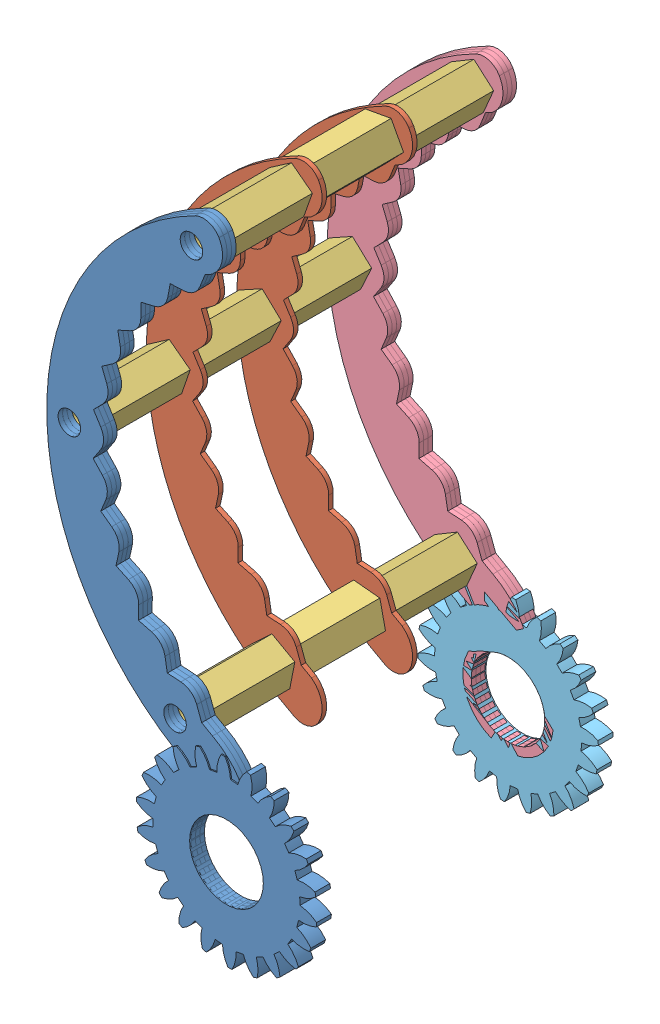
SolidWorks assembly Assem2, configuration Default. Lengths in mm.
Overall size (33.49 73.09 32.76).
17 component instances, 5 part files, 28 mates.
Components (placement in the parent):
- handle1-1: handle1 [Default] at (-7.5398 -35.6958 -27.6488) size (29.97 70.24 1.63)
- kiskac2-1: kiskac2 [Varsayılan] at (50.9968 46.7952 47.8369) size (19.45 53.92 0.5)
- araparca-1: araparca [Varsayılan] at (13.4048 24.2984 43.8369) x (0.977975 0.208721 0) z (0 0 1) size (4.68 4.59 9.5)
- araparca-2: araparca [Varsayılan] at (1.7149 46.7993 43.8369) x (0.9973 0.073437 0) z (0 0 1) size (4.68 4.59 9.5)
- araparca-3: araparca [Varsayılan] at (15.2145 70.4687 43.8369) x (0.997775 0.066667 0) z (0 0 1) size (4.68 4.59 9.5)
- araparca-4: araparca [Varsayılan] at (15.2145 70.4687 33.8369) x (-0.551736 0.834019 0) z (0 0 1) size (4.68 4.59 9.5)
- araparca-5: araparca [Varsayılan] at (1.7149 46.7993 33.8369) x (0.343925 0.938997 0) z (0 0 1) size (4.68 4.59 9.5)
- araparca-6: araparca [Varsayılan] at (13.4048 24.2984 33.8369) x (0.812716 0.582659 0) z (0 0 1) size (4.68 4.59 9.5)
- kiskac2-2: kiskac2 [Varsayılan] at (50.9968 46.7952 37.8369) size (19.45 53.92 0.5)
- araparca-13: araparca [Varsayılan] at (15.2145 70.4687 23.8369) size (4.68 4.59 9.5)
- araparca-14: araparca [Varsayılan] at (13.4048 24.2984 23.8369) size (4.68 4.59 9.5)
- araparca-15: araparca [Varsayılan] at (1.7149 46.7993 23.8369) x (0.999583 -0.028868 0) z (0 0 1) size (4.68 4.59 9.5)
- handle 2-1: handle 2 [Default] at (-16.5479 -33.7454 -75.777) size (32.9 73.09 1.63)
  - kiskac1-1: kiskac1 [Varsayılan] at (65.4233 86.2581 103.6139) size (25 65.23 0.5)
  - gear-3: gear [Default] at (35.7628 47.2729 102.4149) x (0 0 1) z (-0.933673 -0.358127 0) size (1.63 19.86 20.01)
  - kiskac1-2: kiskac1 [Varsayılan] at (65.4233 86.2581 103.1139) size (25 65.23 0.5)
  - kiskac1-3: kiskac1 [Varsayılan] at (65.4233 86.2581 102.6139) size (25 65.23 0.5)
Mates (geometry in assembly coordinates):
- Concentric1: concentric anti-aligned: cylinder of handle1-1 through (15.2145 70.4687 59.5869) axis (0 0 -1) radius 1.25; circle of araparca-3
- Coincident2: coincident anti-aligned: plane of handle1-1 through (14.2809 67.7287 58.0869) normal (0 0 -1); plane of araparca-3 through (15.2145 70.4687 58.0869) normal (0 0 1)
- Concentric2: concentric anti-aligned: circle of handle1-1; cylinder of araparca-1 through (13.4048 24.2984 58.0869) axis (0 0 -1) radius 1.25
- Coincident5: coincident anti-aligned: plane of handle1-1 through (14.2809 67.7287 58.0869) normal (0 0 -1); plane of araparca-1 through (13.4048 24.2984 58.0869) normal (0 0 1)
- Coincident6: coincident anti-aligned: plane of handle1-1 through (14.2809 67.7287 58.0869) normal (0 0 -1); plane of araparca-2 through (1.7149 46.7993 58.0869) normal (0 0 1)
- Concentric3: concentric anti-aligned: circle of handle1-1; cylinder of araparca-2 through (1.7149 46.7993 58.0869) axis (0 0 -1) radius 1.25
- Concentric4: concentric aligned: circle of araparca-3; circle of kiskac2-1
- Coincident9: coincident anti-aligned: plane of araparca-3 through (15.2145 70.4687 48.5869) normal (0 0 -1); plane of kiskac2-1 through (14.2809 67.7287 48.5869) normal (0 0 1)
- Concentric5: concentric aligned: cylinder of araparca-2 through (1.7149 46.7993 58.0869) axis (0 0 -1) radius 1.25; cylinder of kiskac2-1 through (1.7149 46.7993 48.5869) axis (0 0 -1) radius 1.25
- Coincident10: coincident anti-aligned: plane of kiskac2-1 through (14.2809 67.7287 48.0869) normal (0 0 -1); plane of araparca-4 through (15.2145 70.4687 48.0869) normal (0 0 1)
- Coincident11: coincident anti-aligned: plane of kiskac2-1 through (14.2809 67.7287 48.0869) normal (0 0 -1); plane of araparca-5 through (1.7149 46.7993 48.0869) normal (0 0 1)
- Coincident12: coincident anti-aligned: plane of kiskac2-1 through (14.2809 67.7287 48.0869) normal (0 0 -1); plane of araparca-6 through (13.4048 24.2984 48.0869) normal (0 0 1)
- Coincident13: coincident anti-aligned: cylinder of kiskac2-1 through (15.2145 70.4687 48.5869) axis (0 0 -1) radius 1.25; circle of araparca-4
- Concentric6: concentric aligned: circle of kiskac2-1; circle of araparca-5
- Concentric7: concentric aligned: cylinder of araparca-1 through (13.4048 24.2984 58.0869) axis (0 0 -1) radius 1.25; cylinder of araparca-6 through (13.4048 24.2984 48.0869) axis (0 0 -1) radius 1.25
- Coincident15: coincident anti-aligned: plane of araparca-4 through (15.2145 70.4687 38.5869) normal (0 0 -1); plane of kiskac2-2 through (14.2809 67.7287 38.5869) normal (0 0 1)
- Concentric8: concentric anti-aligned: cylinder of araparca-4 through (15.2145 70.4687 48.0869) axis (0 0 -1) radius 1.25; circle of kiskac2-2
- Concentric9: concentric anti-aligned: cylinder of araparca-5 through (1.7149 46.7993 48.0869) axis (0 0 -1) radius 1.25; circle of kiskac2-2
- Concentric10: concentric anti-aligned: cylinder of araparca-6 through (13.4048 24.2984 48.0869) axis (0 0 -1) radius 1.25; circle of kiskac2-2
- Coincident19: coincident anti-aligned: plane of kiskac2-2 through (14.2809 67.7287 38.0869) normal (0 0 -1); plane of araparca-13 through (15.2145 70.4687 38.0869) normal (0 0 1)
- Concentric11: concentric anti-aligned: circle of kiskac2-2; cylinder of araparca-13 through (15.2145 70.4687 38.0869) axis (0 0 -1) radius 1.25
- Concentric12: concentric anti-aligned: circle of kiskac2-2; cylinder of araparca-15 through (1.7149 46.7993 38.0869) axis (0 0 -1) radius 1.25
- Coincident24: coincident anti-aligned: plane of kiskac2-2 through (14.2809 67.7287 38.0869) normal (0 0 -1); plane of araparca-15 through (1.7149 46.7993 38.0869) normal (0 0 1)
- Coincident25: coincident anti-aligned: plane of kiskac2-2 through (14.2809 67.7287 38.0869) normal (0 0 -1); plane of araparca-14 through (13.4048 24.2984 38.0869) normal (0 0 1)
- Concentric13: concentric aligned: cylinder of araparca-6 through (13.4048 24.2984 48.0869) axis (0 0 -1) radius 1.25; cylinder of araparca-14 through (13.4048 24.2984 38.0869) axis (0 0 -1) radius 1.25
- Coincident26: coincident anti-aligned: plane of araparca-14 through (13.4048 24.2984 28.5869) normal (0 0 -1); plane of handle 2-1/kiskac1-1 through (14.2809 67.7287 28.5869) normal (0 0 1)
- Concentric14: concentric anti-aligned: cylinder of araparca-14 through (13.4048 24.2984 38.0869) axis (0 0 -1) radius 1.25; circle of handle 2-1/kiskac1-3
- Concentric16: concentric aligned: cylinder of araparca-13 through (15.2145 70.4687 38.0869) axis (0 0 -1) radius 1.25; cylinder of handle 2-1/kiskac1-3 through (15.2145 70.4687 27.5869) axis (0 0 -1) radius 1.25
